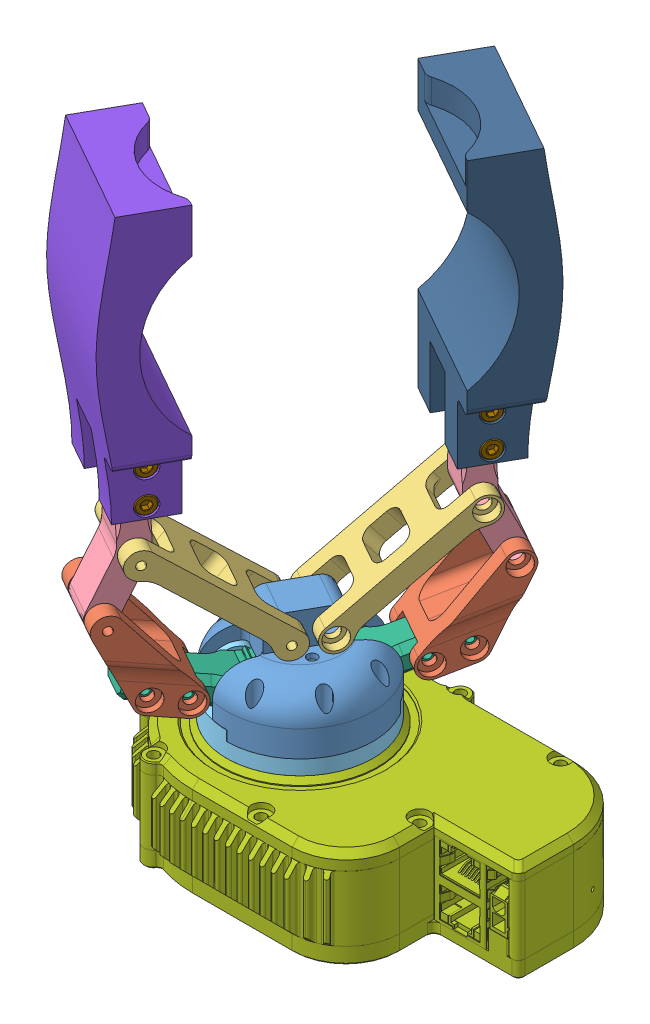
SolidWorks assembly Gripper, configuration Default. Lengths in mm.
Overall size (120.27 189.26 121.01).
23 component instances, 10 part files, 24 mates.
Components (placement in the parent):
- Hebi Motor with Gripper-1: Hebi Motor with Gripper [Default] at (-48.6457 -21.5594 3.9658) size (110.69 120.26 108.93) (flexible)
  - HEBI Robotics-A-2143-02-1: HEBI Robotics-A-2143-02 [Default] at (0 4.6253 0) x (0.491233 0 -0.871028) z (0.871028 0 0.491233) size (112.08 105.21 45) (flexible)
    - HEBI Robotics-A-2143-02_PM-2357-02-1: HEBI Robotics-A-2143-02_PM-2357-02 [Default] at (0 30.9247 0) x (0 0 -1) z (1 0 0) size (45 28 44.67)
    - HEBI Robotics-A-2143-02_PM-2358-02-1: HEBI Robotics-A-2143-02_PM-2358-02 [Default] at (-31.436 29.5333 0) x (0 0 -1) z (0.966127 -0.258068 0) size (23 26 33)
    - HEBI Robotics-A-2143-02_PM-2358-02-2: HEBI Robotics-A-2143-02_PM-2358-02 [Default] at (31.4354 29.5354 0) x (0 0 1) z (-0.966125 -0.258076 0) size (23 26 33)
    - HEBI Robotics-A-2143-02_PM-2359-02-1: HEBI Robotics-A-2143-02_PM-2359-02 [Default] at (21.9996 52.7813 0) x (0 0 1) z (0.775123 0.631811 0) size (23 8 51.86)
    - HEBI Robotics-A-2143-02_PM-2359-02-2: HEBI Robotics-A-2143-02_PM-2359-02 [Default] at (-22.0004 52.7803 0) x (0 0 -1) z (-0.775159 0.631767 0) size (23 8 51.86)
    - HEBI Robotics-A-2143-02_PM-2360-02-1: HEBI Robotics-A-2143-02_PM-2360-02 [Default] at (-39.0008 66.6359 0) x (-1 -0.000025 0) z (0 0 -1) size (15.5 54 12.08)
    - HEBI Robotics-A-2143-02_PM-2360-02-2: HEBI Robotics-A-2143-02_PM-2360-02 [Default] at (38.9992 66.6378 0) x (1 0.000025 0) z (0 0 1) size (15.5 54 12.08)
    - HEBI Robotics-A-2055-01_PM-2218-01-1: HEBI Robotics-A-2055-01_PM-2218-01 [Default] at (0 11.4247 0) size (45 32.5 45)
    - HEBI Robotics-A-2055-01_PM-2221-01-1: HEBI Robotics-A-2055-01_PM-2221-01 [Default] at (12.5 22.9247 0) x (0.966125 0.258076 0) z (0 0 1) size (35.49 9.86 12)
    - HEBI Robotics-A-2055-01_PM-2221-01-2: HEBI Robotics-A-2055-01_PM-2221-01 [Default] at (-12.5 22.9247 0) x (-0.966162 0.257934 0) z (0 0 -1) size (35.49 9.86 12)
  - HEBI Robotics-X5-Export-2021-1: HEBI Robotics-X5-Export-2021 [Default] x (1 0 0) z (0 1 0) size (109.71 73.14 31.05)
- gripper finger-1: gripper finger [Default] at (-68.8768 115.2018 7.2675) x (0.491233 0 -0.871028) z (0 -1 0) size (25.6 40 87.5)
- 91292A114_M3-0.5x12-1: 91292A114_M3-0.5x12 [91292A114] at (-67.1077 78.7018 38.3302) x (-0.455531 -0.374262 0.807724) z (-0.871028 0 -0.491233) size (5.5 5.5 15.23)
- 91292A114_M3-0.5x12-2: 91292A114_M3-0.5x12 [91292A114] at (-67.1077 68.7018 38.3302) x (-0.424928 -0.501733 0.753459) z (-0.871028 0 -0.491233) size (5.5 5.5 15.23)
- 91292A114_M3-0.5x12-4: 91292A114_M3-0.5x12 [91292A114] at (-68.5013 78.7018 37.5442) x (-0.060556 -0.992373 0.107375) z (0.871028 0 0.491233) size (5.5 5.5 15.23)
- 91292A114_M3-0.5x12-6: 91292A114_M3-0.5x12 [91292A114] at (-68.5013 68.7018 37.5442) x (0.028132 -0.998359 -0.049882) z (0.871028 0 0.491233) size (5.5 5.5 15.23)
- gripper finger mirror-1: gripper finger mirror [Default] at (-56.2894 115.2031 -15.0518) x (0.491233 0.000026 -0.871028) z (0.000013 -1 -0.000022) size (25.6 40 87.5)
- 91292A114_M3-0.5x12-15: 91292A114_M3-0.5x12 [91292A114] at (-28.7915 78.7037 -29.61) x (-0.424928 -0.501733 0.753459) z (-0.871028 0 -0.491233) size (5.5 5.5 15.23)
- 91292A114_M3-0.5x12-17: 91292A114_M3-0.5x12 [91292A114] at (-28.7914 68.7037 -29.6102) x (-0.394099 -0.596967 0.698796) z (-0.871028 0 -0.491233) size (5.5 5.5 15.23)
- 91292A114_M3-0.5x12-20: 91292A114_M3-0.5x12 [91292A114] at (-30.1852 78.7037 -30.396) x (0.028132 -0.998359 -0.049882) z (0.871028 0 0.491233) size (5.5 5.5 15.23)
- 91292A114_M3-0.5x12-22: 91292A114_M3-0.5x12 [91292A114] at (-30.1851 68.7037 -30.3962) x (0.117181 -0.971131 -0.20778) z (0.871028 0 0.491233) size (5.5 5.5 15.23)
Mates (geometry in assembly coordinates):
- Width1: width anti-aligned: plane of gripper finger-1 through (-41.0039 115.2018 22.9869) normal (0.871028 0 0.491233); plane of Hebi Motor with Gripper-1/HEBI Robotics-A-2143-02-1/HEBI Robotics-A-2143-02_PM-2360-02-1 through (-68.8768 115.2018 7.2675) normal (-0.871028 0 -0.491233); plane of gripper finger-1 through (-76.7144 33.7016 41.5216) normal (-0.871028 0 -0.491233); plane of Hebi Motor with Gripper-1/HEBI Robotics-A-2143-02-1/HEBI Robotics-A-2143-02_PM-2360-02-1 through (-66.2621 33.7016 47.4164) normal (0.871028 0 0.491233)
- Width2: width anti-aligned: plane of gripper finger-2 through (-41.2816 119.2515 20.816) normal (-0.103227 0 0.994658); plane of Hebi Motor with Gripper-1/HEBI Robotics-A-2143-02-1/HEBI Robotics-A-2143-02_PM-2360-02-2 through (-37.9783 119.2515 -11.013) normal (0.103227 0 -0.994658); plane of gripper finger-2 through (-31.0297 33.7039 -39.4841) normal (-0.871028 0 -0.491233); plane of Hebi Motor with Gripper-1/HEBI Robotics-A-2143-02-1/HEBI Robotics-A-2143-02_PM-2360-02-2 through (-20.5774 33.7039 -33.5893) normal (0.871028 0 0.491233)
- Concentric1: concentric aligned: cylinder of Hebi Motor with Gripper-1/HEBI Robotics-A-2143-02-1/HEBI Robotics-A-2143-02_PM-2360-02-1 through (-62.5784 78.7018 40.8846) axis (0.871028 0 0.491233) radius 1.25; cylinder of gripper finger-1 through (-81.741 78.7018 30.0775) axis (0.871028 0 0.491233) radius 1.75
- Concentric2: concentric aligned: cylinder of Hebi Motor with Gripper-1/HEBI Robotics-A-2143-02-1/HEBI Robotics-A-2143-02_PM-2360-02-2 through (-34.7145 78.7037 -32.9504) axis (-0.871028 0 -0.491233) radius 1.25; cylinder of gripper finger-2 through (-15.234 82.7515 23.5193) axis (0.103227 0 -0.994658) radius 1.75
- Coincident1: coincident anti-aligned: plane of gripper finger-1 through (-56.6554 78.7018 44.225) normal (0.871028 0 0.491233); plane of 91292A114_M3-0.5x12-1 through (-56.6554 78.7018 44.225) normal (-0.871028 0 -0.491233)
- Concentric3: concentric anti-aligned: cylinder of gripper finger-1 through (-56.6554 78.7018 44.225) axis (0.871028 0 0.491233) radius 3; cylinder of 91292A114_M3-0.5x12-1 through (-54.0423 78.7018 45.6987) axis (-0.871028 0 -0.491233) radius 2.75
- Coincident2: coincident anti-aligned: plane of gripper finger-1 through (-56.6554 68.7018 44.225) normal (0.871028 0 0.491233); plane of 91292A114_M3-0.5x12-2 through (-56.6554 68.7018 44.225) normal (-0.871028 0 -0.491233)
- Concentric4: concentric anti-aligned: cylinder of gripper finger-1 through (-56.6554 68.7018 44.225) axis (0.871028 0 0.491233) radius 3; cylinder of 91292A114_M3-0.5x12-2 through (-54.0423 68.7018 45.6987) axis (-0.871028 0 -0.491233) radius 2.75
- Coincident3: coincident anti-aligned: plane of gripper finger-1 through (-78.9537 78.7018 31.6495) normal (-0.871028 0 -0.491233); plane of 91292A114_M3-0.5x12-4 through (-78.9537 78.7018 31.6495) normal (0.871028 0 0.491233)
- Concentric5: concentric anti-aligned: cylinder of gripper finger-1 through (-78.9537 78.7018 31.6495) axis (-0.871028 0 -0.491233) radius 3; cylinder of 91292A114_M3-0.5x12-4 through (-81.5668 78.7018 30.1758) axis (0.871028 0 0.491233) radius 2.75
- Coincident4: coincident anti-aligned: plane of gripper finger-1 through (-78.9537 68.7018 31.6495) normal (-0.871028 0 -0.491233); plane of 91292A114_M3-0.5x12-6 through (-78.9537 68.7018 31.6495) normal (0.871028 0 0.491233)
- Concentric6: concentric anti-aligned: cylinder of gripper finger-1 through (-78.9537 68.7018 31.6495) axis (-0.871028 0 -0.491233) radius 3; cylinder of 91292A114_M3-0.5x12-6 through (-81.5668 68.7018 30.1758) axis (0.871028 0 0.491233) radius 2.75
- Coincident5: coincident anti-aligned: plane of gripper finger-2 through (-12.2611 82.7515 -5.1269) normal (0.103227 0 -0.994658); plane of 91292A114_M3-0.5x12-8 through (-12.2611 82.7515 -5.1269) normal (-0.103227 0 0.994658)
- Concentric7: concentric anti-aligned: cylinder of gripper finger-2 through (-12.2611 82.7515 -5.1269) axis (0.103227 0 -0.994658) radius 3; cylinder of 91292A114_M3-0.5x12-8 through (-11.9514 82.7515 -8.1109) axis (-0.103227 0 0.994658) radius 2.75
- Width3: width anti-aligned: plane of gripper finger mirror-1 through (-28.4165 115.2031 0.6676) normal (0.871028 0 0.491233); plane of Hebi Motor with Gripper-1/HEBI Robotics-A-2143-02-1/HEBI Robotics-A-2143-02_PM-2360-02-2 through (-56.2894 115.2031 -15.0518) normal (-0.871028 0 -0.491233); plane of gripper finger mirror-1 through (-31.0297 33.7039 -39.4841) normal (-0.871028 0 -0.491233); plane of Hebi Motor with Gripper-1/HEBI Robotics-A-2143-02-1/HEBI Robotics-A-2143-02_PM-2360-02-2 through (-20.5774 33.7039 -33.5893) normal (0.871028 0 0.491233)
- Concentric12: concentric anti-aligned: circle of Hebi Motor with Gripper-1/HEBI Robotics-A-2143-02-1/HEBI Robotics-A-2143-02_PM-2360-02-2; circle of gripper finger mirror-1
- Coincident6: coincident anti-aligned: plane of gripper finger mirror-1 through (-18.3392 78.7037 -23.7152) normal (0.871028 0 0.491233); plane of 91292A114_M3-0.5x12-15 through (-18.3392 78.7037 -23.7152) normal (-0.871028 0 -0.491233)
- Concentric13: concentric anti-aligned: cylinder of gripper finger mirror-1 through (-18.3392 78.7037 -23.7152) axis (0.871028 0 0.491233) radius 3; cylinder of 91292A114_M3-0.5x12-15 through (-15.7261 78.7037 -22.2415) axis (-0.871028 0 -0.491233) radius 2.75
- Coincident7: coincident anti-aligned: plane of gripper finger mirror-1 through (-18.3391 68.7037 -23.7154) normal (0.871028 0 0.491233); plane of 91292A114_M3-0.5x12-17 through (-18.3391 68.7037 -23.7154) normal (-0.871028 0 -0.491233)
- Concentric14: concentric anti-aligned: cylinder of gripper finger mirror-1 through (-18.3391 68.7037 -23.7154) axis (0.871028 0 0.491233) radius 3; cylinder of 91292A114_M3-0.5x12-17 through (-15.726 68.7037 -22.2417) axis (-0.871028 0 -0.491233) radius 2.75
- Coincident9: coincident anti-aligned: plane of gripper finger mirror-1 through (-40.6375 78.7037 -36.2907) normal (-0.871028 0 -0.491233); plane of 91292A114_M3-0.5x12-20 through (-40.6375 78.7037 -36.2907) normal (0.871028 0 0.491233)
- Concentric15: concentric anti-aligned: cylinder of gripper finger mirror-1 through (-40.6375 78.7037 -36.2907) axis (-0.871028 0 -0.491233) radius 3; cylinder of 91292A114_M3-0.5x12-20 through (-43.2506 78.7037 -37.7644) axis (0.871028 0 0.491233) radius 2.75
- Coincident10: coincident anti-aligned: plane of gripper finger mirror-1 through (-40.6374 68.7037 -36.291) normal (-0.871028 0 -0.491233); plane of 91292A114_M3-0.5x12-22 through (-40.6374 68.7037 -36.291) normal (0.871028 0 0.491233)
- Concentric16: concentric anti-aligned: cylinder of gripper finger mirror-1 through (-40.6374 68.7037 -36.291) axis (-0.871028 0 -0.491233) radius 3; cylinder of 91292A114_M3-0.5x12-22 through (-43.2505 68.7037 -37.7647) axis (0.871028 0 0.491233) radius 2.75
